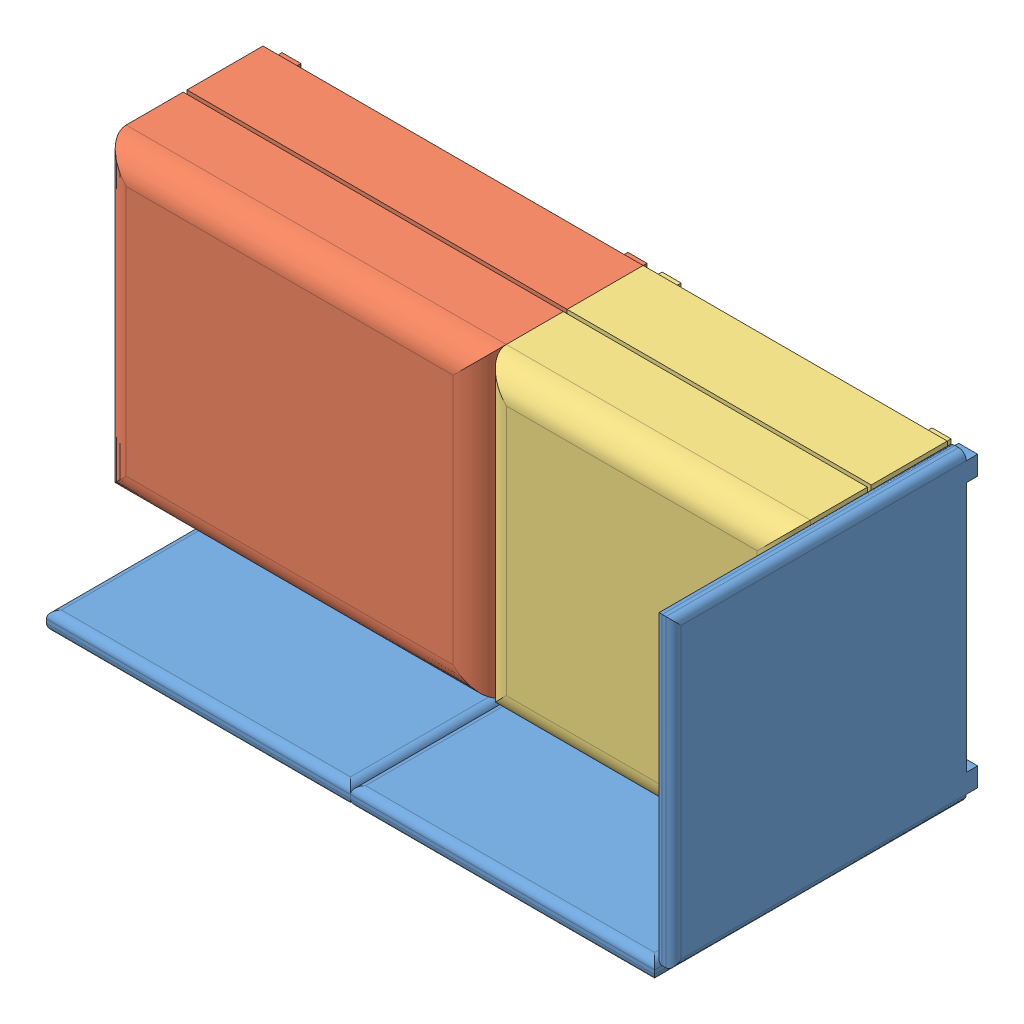
SolidWorks assembly Sofa-R, configuration Standard. Lengths in mm.
Overall size (1850 850 800).
5 component instances, 3 part files, 12 mates.
Components (placement in the parent):
- Rückenstütze-80x80-1: Rückenstütze-80x80 [Standard] at (48.0974 -746.2493 765.6126) size (800 50 800)
- Sitzelement-1: Sitzelement [Standard] at (-51.9026 -321.2493 795.6126) x (0 -1 0) z (-1 0 0) size (800 460 1000)
- Sitzelement-mit-Aufb-1: Sitzelement-mit-Aufb [Standard] at (848.0974 -321.2493 795.6126) x (1 0 0) z (0 -1 0) size (800 460 800)
- Rückenstütze-80x80-2: Rückenstütze-80x80 [Standard] at (848.0974 -746.2493 765.6126) size (800 50 800)
- Rückenstütze-80x80-3: Rückenstütze-80x80 [Standard] at (1273.0974 -321.2493 765.6126) x (0 -1 0) z (0 0 1) size (800 50 800)
Mates (geometry in assembly coordinates):
- Deckungsgleich2: coincident: plane of Rückenstütze-80x80-1 through (48.0974 -1096.6252 765.6126) normal (0 0 -1); plane of Sitzelement-1 through (-51.9026 -321.2493 765.6126) normal (0 0 -1)
- Deckungsgleich3: coincident: plane of Rückenstütze-80x80-1 through (448.0974 -1121.6252 1565.6126) normal (1 0 0); plane of Sitzelement-1 through (448.0974 78.7507 995.6126) normal (1 0 0)
- Deckungsgleich4: coincident aligned: plane of Sitzelement-1 through (-278.9274 -321.2493 800) normal (0 0 -1); plane of Sitzelement-mit-Aufb-1 through (621.0726 -321.2493 800) normal (0 0 -1)
- Deckungsgleich5: coincident anti-aligned: plane of Sitzelement-1 through (221.0726 78.7507 1030) normal (1 0 0); plane of Sitzelement-mit-Aufb-1 through (221.0726 -721.2493 1030) normal (-1 0 0)
- Deckungsgleich6: coincident aligned: plane of Sitzelement-1 through (-778.9274 78.7507 1030) normal (0 1 0); plane of Sitzelement-mit-Aufb-1 through (221.0726 78.7507 1030) normal (0 1 0)
- Deckungsgleich7: coincident: plane of Sitzelement-mit-Aufb-1 through (848.0974 -321.2493 765.6126) normal (0 0 -1); plane of Rückenstütze-80x80-2 through (848.0974 -910.5625 765.6126) normal (0 0 -1)
- Deckungsgleich8: coincident aligned: plane of Sitzelement-mit-Aufb-1 through (621.0726 -321.2493 800) normal (0 0 -1); plane of Rückenstütze-80x80-3 through (1046.0726 -321.2493 800) normal (0 0 -1)
- Deckungsgleich10: coincident: plane of Sitzelement-mit-Aufb-1 through (1248.0974 -721.2493 995.6126) normal (1 0 0); plane of Rückenstütze-80x80-2 through (1248.0974 -935.5625 1565.6126) normal (1 0 0)
- Deckungsgleich11: coincident anti-aligned: plane of Sitzelement-mit-Aufb-1 through (1021.0726 -721.2493 1030) normal (1 0 0); plane of Rückenstütze-80x80-3 through (1021.0726 58.7507 830) normal (-1 0 0)
- Deckungsgleich12: coincident aligned: plane of Sitzelement-mit-Aufb-1 through (221.0726 78.7507 1030) normal (0 1 0); plane of Rückenstütze-80x80-3 through (1021.0726 78.7507 1600) normal (0 1 0)
- Deckungsgleich13: coincident anti-aligned: plane of Rückenstütze-80x80-1 through (-331.9026 -721.2493 795.6126) normal (0 1 0); plane of Sitzelement-1 through (-551.9026 -721.2493 995.6126) normal (0 -1 0)
- Deckungsgleich14: coincident anti-aligned: plane of Sitzelement-mit-Aufb-1 through (448.0974 -721.2493 995.6126) normal (0 -1 0); plane of Rückenstütze-80x80-2 through (468.0974 -721.2493 795.6126) normal (0 1 0)
